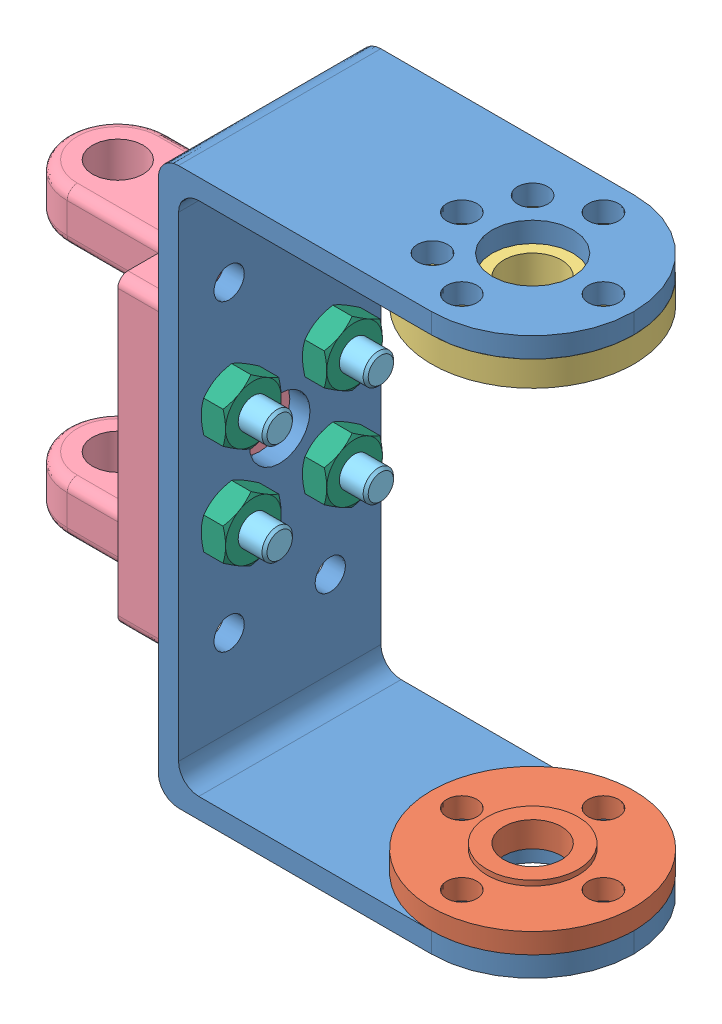
SolidWorks assembly moteur-bras-v2, configuration Défaut. Lengths in mm.
Overall size (56 55 20).
12 component instances, 6 part files, 28 mates.
Components (placement in the parent):
- moteur-support-mobile-v2-1: moteur-support-mobile-v2 [Défaut] at (18.386 -2.2808 45) size (37 55 20)
- moteur-platine_libre-1: moteur-platine_libre [Défaut] at (8.386 -27.7808 55) x (1 0 0) z (0 1 0) size (20 20 2.5)
- moteur-platine_moteur-1: moteur-platine_moteur [Défaut] at (8.386 23.2192 55) x (1 0 0) z (0 -1 0) size (20 20 4.5)
- support-fourchette-chc_m3-1: support-fourchette-chc_m3 [Défaut] at (-32.614 -2.2808 55) x (0 1 0) z (0 0 1) size (30 19 20)
- vis-chc-1: vis-chc [Vis CHC M3x8] at (-19.614 2.7192 50) x (0 0.164744 0.986336) z (0 -0.986336 0.164744) size (5.5 11 5.5)
- ecrou-h-1: ecrou-h [6012 HU M3] at (-16.614 2.7192 50) x (0 0.866025 0.5) z (0 -0.5 0.866025) size (5.5 2.4 6.35)
- ecrou-h-2: ecrou-h [6012 HU M3] at (-14.214 2.7192 60) x (0 -0.866025 -0.5) z (0 -0.5 0.866025) size (5.5 2.4 6.35)
- ecrou-h-3: ecrou-h [6012 HU M3] at (-14.214 -7.2808 50) x (0 -0.866025 -0.5) z (0 -0.5 0.866025) size (5.5 2.4 6.35)
- ecrou-h-4: ecrou-h [6012 HU M3] at (-14.214 -7.2808 60) x (0 -0.866025 -0.5) z (0 -0.5 0.866025) size (5.5 2.4 6.35)
- vis-chc-2: vis-chc [Vis CHC M3x8] at (-19.614 2.7192 60) x (0 -0.933966 -0.357361) z (0 0.357361 -0.933966) size (5.5 11 5.5)
- vis-chc-3: vis-chc [Vis CHC M3x8] at (-19.614 -7.2808 60) x (0 0.351541 0.936173) z (0 -0.936173 0.351541) size (5.5 11 5.5)
- vis-chc-4: vis-chc [Vis CHC M3x8] at (-19.614 -7.2808 50) x (0 -0.47591 0.879494) z (0 -0.879494 -0.47591) size (5.5 11 5.5)
Mates (geometry in assembly coordinates):
- Coïncidente1: coincident anti-aligned: plane of moteur-support-mobile-v2-1 through (-14.614 23.2192 65) normal (0 -1 0); plane of moteur-platine_moteur-1 through (8.386 23.2192 55) normal (0 1 0)
- Coïncidente2: coincident anti-aligned: plane of moteur-support-mobile-v2-1 through (18.386 -27.7808 65) normal (0 1 0); plane of moteur-platine_libre-1 through (8.386 -27.7808 55) normal (0 -1 0)
- Coaxiale1: concentric aligned: cylinder of moteur-support-mobile-v2-1 through (1.386 -29.7808 55) axis (0 1 0) radius 1.5; cylinder of moteur-platine_libre-1 through (1.386 -27.7808 55) axis (0 1 0) radius 1.5
- Coaxiale2: concentric anti-aligned: cylinder of moteur-support-mobile-v2-1 through (8.386 -29.7808 55) axis (0 1 0) radius 4; cylinder of moteur-platine_libre-1 through (8.386 -25.7808 55) axis (0 -1 0) radius 2.85
- Coaxiale3: concentric aligned: cylinder of moteur-support-mobile-v2-1 through (8.386 -29.7808 55) axis (0 1 0) radius 4; cylinder of moteur-platine_moteur-1 through (8.386 20.7192 55) axis (0 1 0) radius 2.85
- Coaxiale4: concentric anti-aligned: cylinder of moteur-support-mobile-v2-1 through (8.386 -29.7808 62) axis (0 1 0) radius 1.5; cylinder of moteur-platine_moteur-1 through (8.386 23.2192 62) axis (0 -1 0) radius 1.5
- Coïncidente3: coincident anti-aligned: plane of moteur-support-mobile-v2-1 through (-18.614 23.2192 65) normal (-1 0 0); plane of support-fourchette-ecrou_m2-1 through (-18.614 -2.2808 55) normal (1 0 0)
- Coaxiale5: concentric aligned: cylinder of moteur-support-mobile-v2-1 through (18.387 2.7192 50) axis (-1 0 0) radius 1.5; cylinder of support-fourchette-ecrou_m2-1 through (-18.613 2.7192 50) axis (-1 0 0) radius 1.5
- Coaxiale6: concentric aligned: cylinder of support-fourchette-chc_m3-1 through (-18.613 2.7192 50) axis (-1 0 0) radius 1.5; cylinder of vis-chc-m2-1 through (-11.614 2.7192 50) axis (-1 0 0) radius 1.5
- Coïncidente4: coincident anti-aligned: plane of moteur-support-mobile-v2-1 through (-16.614 -25.7808 65) normal (1 0 0); plane of ecrou-h-m2-1 through (-16.614 5.8946 50) normal (-1 0 0)
- Coaxiale7: concentric aligned: cylinder of moteur-support-mobile-v2-1 through (18.387 2.7192 50) axis (-1 0 0) radius 1.5; cylinder of ecrou-h-m2-1 through (-14.214 2.7192 50) axis (-1 0 0) radius 1.2295
- Parallèle1: parallel aligned: plane of moteur-support-mobile-v2-1 through (-16.614 23.2192 45) normal (0 0 -1); plane of ecrou-h-m2-1 through (-14.214 4.3069 47.25) normal (0 0 -1)
- Coaxiale8: concentric aligned: cylinder of moteur-support-mobile-v2-1 through (18.387 2.7192 60) axis (-1 0 0) radius 1.5; cylinder of vis-chc-2 through (-11.614 2.7192 60) axis (-1 0 0) radius 1.5
- Coaxiale9: concentric aligned: cylinder of moteur-support-mobile-v2-1 through (18.387 -7.2808 60) axis (-1 0 0) radius 1.5; cylinder of vis-chc-3 through (-11.614 -7.2808 60) axis (-1 0 0) radius 1.5
- Coaxiale10: concentric aligned: cylinder of moteur-support-mobile-v2-1 through (18.387 -7.2808 50) axis (-1 0 0) radius 1.5; cylinder of vis-chc-4 through (-11.614 -7.2808 50) axis (-1 0 0) radius 1.5
- Coïncidente8: coincident anti-aligned: plane of support-fourchette-chc_m3-1 through (-19.614 2.7192 50) normal (-1 0 0); plane of vis-chc-1 through (-19.614 2.7192 50) normal (1 0 0)
- Coïncidente9: coincident anti-aligned: plane of support-fourchette-chc_m3-1 through (-19.614 2.7192 60) normal (-1 0 0); plane of vis-chc-2 through (-19.614 2.7192 60) normal (1 0 0)
- Coïncidente10: coincident anti-aligned: plane of support-fourchette-chc_m3-1 through (-19.614 -7.2808 60) normal (-1 0 0); plane of vis-chc-3 through (-19.614 -7.2808 60) normal (1 0 0)
- Coïncidente11: coincident anti-aligned: plane of support-fourchette-chc_m3-1 through (-19.614 -7.2808 50) normal (-1 0 0); plane of vis-chc-4 through (-19.614 -7.2808 50) normal (1 0 0)
- Coaxiale11: concentric anti-aligned: cylinder of ecrou-h-2 through (-16.614 2.7192 60) axis (1 0 0) radius 1.2295; cylinder of vis-chc-2 through (-11.614 2.7192 60) axis (-1 0 0) radius 1.5
- Coaxiale12: concentric anti-aligned: cylinder of ecrou-h-3 through (-16.614 -7.2808 50) axis (1 0 0) radius 1.2295; cylinder of vis-chc-4 through (-11.614 -7.2808 50) axis (-1 0 0) radius 1.5
- Coaxiale13: concentric anti-aligned: cylinder of ecrou-h-4 through (-16.614 -7.2808 60) axis (1 0 0) radius 1.2295; cylinder of vis-chc-3 through (-11.614 -7.2808 60) axis (-1 0 0) radius 1.5
- Coïncidente12: coincident anti-aligned: plane of moteur-support-mobile-v2-1 through (-16.614 -25.7808 65) normal (1 0 0); plane of ecrou-h-4 through (-16.614 -8.8685 57.25) normal (-1 0 0)
- Coïncidente13: coincident anti-aligned: plane of moteur-support-mobile-v2-1 through (-16.614 -25.7808 65) normal (1 0 0); plane of ecrou-h-3 through (-16.614 -8.8685 47.25) normal (-1 0 0)
- Coïncidente14: coincident anti-aligned: plane of moteur-support-mobile-v2-1 through (-16.614 -25.7808 65) normal (1 0 0); plane of ecrou-h-2 through (-16.614 1.1315 57.25) normal (-1 0 0)
- Parallèle2: parallel aligned: plane of moteur-support-mobile-v2-1 through (-16.614 23.2192 65) normal (0 0 1); plane of ecrou-h-2 through (-16.614 4.3069 62.75) normal (0 0 1)
- Parallèle3: parallel aligned: plane of moteur-support-mobile-v2-1 through (-16.614 23.2192 65) normal (0 0 1); plane of ecrou-h-4 through (-16.614 -5.6931 62.75) normal (0 0 1)
- Parallèle4: parallel aligned: plane of moteur-support-mobile-v2-1 through (-16.614 23.2192 45) normal (0 0 -1); plane of ecrou-h-3 through (-16.614 -8.8685 47.25) normal (0 0 -1)
